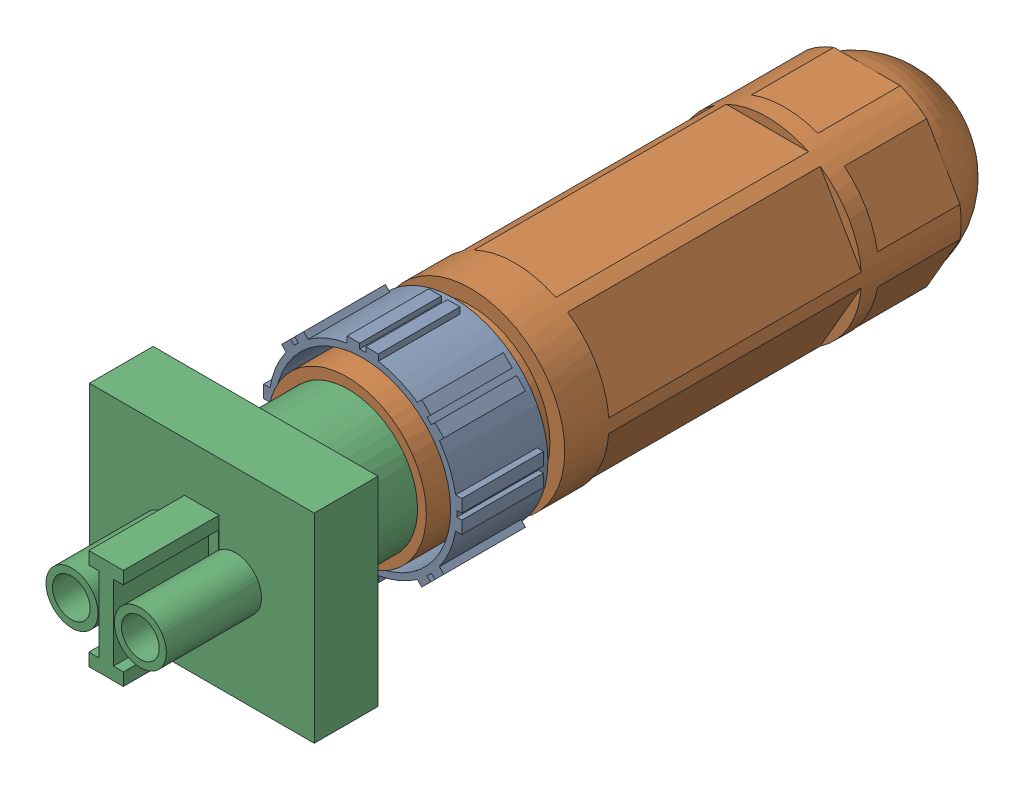
SolidWorks assembly Motor Receptacle Assembly, configuration Default. Lengths in mm.
Overall size (35.81 31.75 132.31).
2 component instances, 2 part files, 2 mates.
Components (placement in the parent):
- Motor Plug Receptacle Male piece-1: Motor Plug Receptacle Male piece [Default] at (-26.1727 -4.3211 -19.8403) size (31.56 31.56 92.43)
- Motor Plug Receptacle Female piece-1: Motor Plug Receptacle Female piece [Default] at (-24.6608 -4.3211 87.6017) x (0 -1 0) z (0 0 -1) size (31.75 35.81 39.88)
Mates (geometry in assembly coordinates):
- Coincident1: coincident anti-aligned: plane of Motor Plug Receptacle Male piece-1 through (-26.1727 -4.3211 62.9637) normal (0 0 1); plane of Motor Plug Receptacle Female piece-1 through (-25.9499 -4.2963 62.9637) normal (0 0 -1)
- Concentric2: concentric aligned: cylinder of Motor Plug Receptacle Male piece-1 through (-21.1727 -4.3211 62.9637) axis (0 0 -1) radius 1.8; cylinder of Motor Plug Receptacle Female piece-1 through (-21.1727 -4.3211 71.4637) axis (0 0 -1) radius 2
